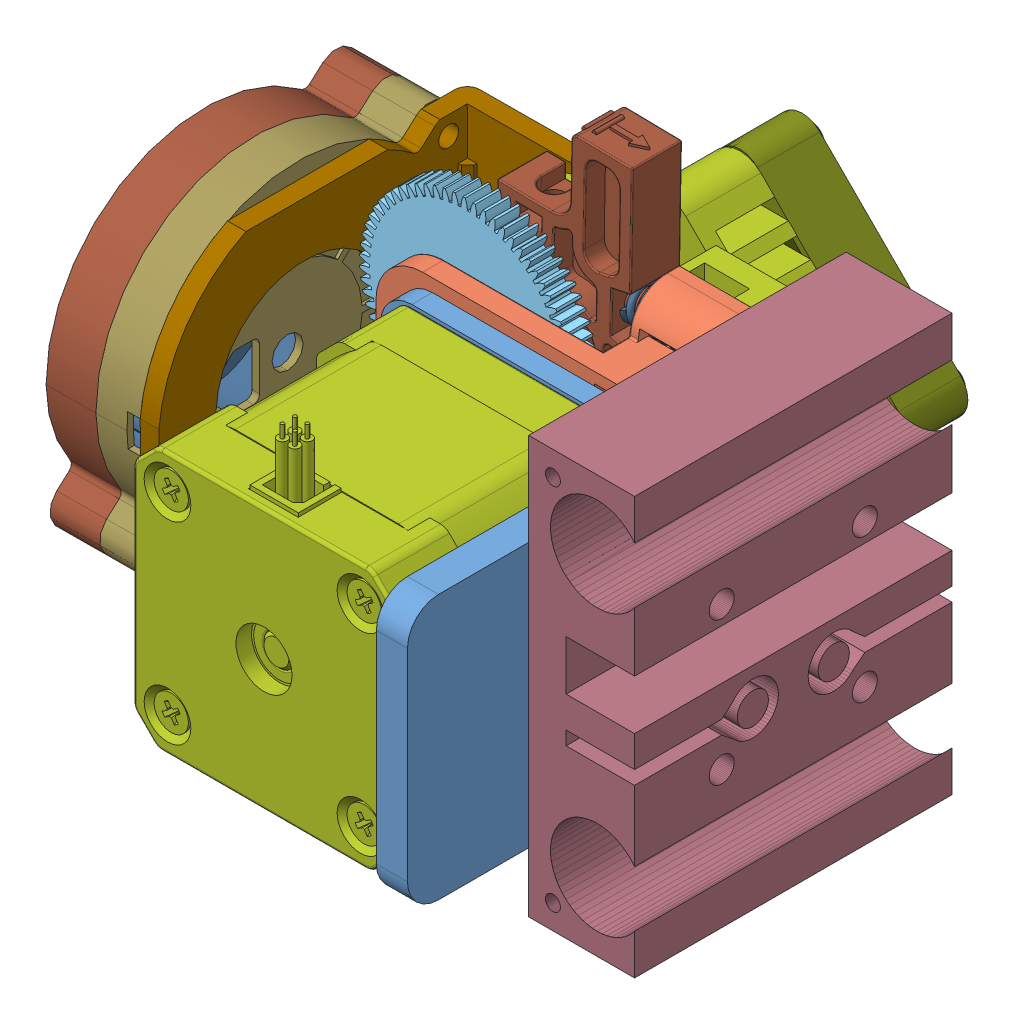
SolidWorks assembly soportetitan, configuration Predeterminado. Lengths in mm.
Overall size (99.83 91.4 93.62).
41 component instances, 31 part files, 14 mates.
Components (placement in the parent):
- soportetitan-1: soportetitan [Predeterminado] at origin size (59.5 44.5 64.5)
- e3d titan areo 1.751-1: e3d titan areo 1.751 [Predeterminado] at (-26.25 -7.1304 -22.9203) x (1 0 0) z (0 1 0) size (64.29 55.52 89.93)
  - Base-1: Base [Predeterminado] at origin size (46 23.41 49.98)
  - 9x5x3mm bearing-1: 9x5x3mm bearing [Predeterminado] at (-15.5 4 15.5) x (1 0 0) z (0 -1 0) size (9 9 3)
  - hobbed wheel-1: hobbed wheel [Predeterminado] at (-15.5 1.6 15.5) x (-0.447437 0 0.894315) z (0 1 0) size (8.6 8.58 20.6)
  - filament gear-1: filament gear [Predeterminado] at (-15.5 8.55 15.5) x (-0.894315 0 -0.447437) z (0 -1 0) size (34 34 4)
  - motor gear-1: motor gear [Predeterminado] at (0 8.5 0) x (-0.681998 0 -0.731354) z (0 -1 0) size (11.99 11.99 9)
  - cover-1: cover [Predeterminado] at (0 24.9 0) x (1 0 0) z (0 0 -1) size (52.63 28.17 55.14)
  - 9x5x3mm bearing-2: 9x5x3mm bearing [Predeterminado] at (-15.5 22.8 15.5) x (1 0 0) z (0 -1 0) size (9 9 3)
  - m3x8-1: m3x8 [Predeterminado] at (20.7 13.6 23.3) x (0 0 1) z (0 1 0) size (5.69 9.65 5.69)
  - M3 nut-1: M3 nut [Predeterminado] at (16.7 13.6 23.3) x (0 1 0) z (0 0 1) size (6.19 2.71 6.57)
  - idler spring-1: idler spring [Predeterminado] at (14.287 13.6 23.3) x (0 0 1) z (-1 0 0) size (6.43 6.45 12.02)
  - tensioner-1: tensioner [Predeterminado] at (0 13.6 0) x (0 -1 0) z (0.017452 0 0.999848) size (8.2 21.54 50.88)
  - idler bearing pin-1: idler bearing pin [Predeterminado] at (-5.2287 9.6 15.5936) x (0.999848 0 -0.017452) z (0 1 0) size (3.04 3.15 9)
  - idler bearing-1: idler bearing [Predeterminado] at (-5.2287 13.6 15.5936) x (0.999848 0 -0.017452) z (0 1 0) size (10 10 4)
  - guide tube-1: guide tube [Predeterminado] at (-10.9 13.6 -7.9) x (-1 0 0) z (0 0 1) size (10.9 16.1 22.25)
  - ISO 7380 - M3 x 28 v1-1: ISO 7380 - M3 x 28 v1 [Predeterminado] at (-15.5 25.94 15.5) x (0 -1 0) z (0 0 1) size (14.65 5.7 5.7)
  - ISO 7380 - M3 x 28 v1-2: ISO 7380 - M3 x 28 v1 [Predeterminado] at (15.5 25.94 15.5) x (0 -1 0) z (0 0 1) size (14.65 5.7 5.7)
  - ISO 7380 - M3 x 28 v1-3: ISO 7380 - M3 x 28 v1 [Predeterminado] at (15.5 25.94 -15.5) x (0 -1 0) z (0 0 1) size (14.65 5.7 5.7)
  - ISO 7380 - M3 x 28 v1-4: ISO 7380 - M3 x 28 v1 [Predeterminado] at (-21.7 25.94 -14.7) x (0 -1 0) z (0 0 -1) size (14.65 5.7 5.7)
  - Fan 40 X 40 X 10 v4-1: Fan 40 X 40 X 10 v4 [Predeterminado] at (-2.3 40.465 3.8274) x (0.707107 0 0.707107) z (-0.707107 0 0.707107) size (40 10.59 40)
  - E3D v6 HotEnd - Heatbreak-1: E3D v6 HotEnd - Heatbreak [Predeterminado] at (-10.9 13.6 -31.7812) x (0 1 0) z (0 0 -1) size (7 7 21.9)
  - E3D v6 HotEnd - Nozzle-1: E3D v6 HotEnd - Nozzle [Predeterminado] at (-10.9 13.6 -42.2812) x (0 1 0) z (0 0 -1) size (8.08 7 12.5)
  - E3D v6 HotEnd - Heat Block-1: E3D v6 HotEnd - Heat Block [Predeterminado] at (-2.9 -1.9 -38.0312) x (0 1 0) z (1 0 0) size (20 11.5 16)
  - Ceramic Cartridge Heater-1: Ceramic Cartridge Heater [Predeterminado] at (-0.9 6.6 -34.0312) x (0 0 1) z (1 0 0) size (6 18 29.25)
  - Thermistor-1: Thermistor [Predeterminado] at (-7 16.1 -36.0312) x (0 -0.5 0.866025) z (-1 0 0) size (1.5 1.5 7.6)
  - HEXAGON SOCKET HEAD CAP SCREWS_SCB3-4-1: HEXAGON SOCKET HEAD CAP SCREWS_SCB3-4 [Predeterminado] at (-2.4 14.6 -33.2312) x (0 1 0) z (1 0 0) size (5.5 5.5 7)
  - HEXAGON SOCKET HEAD CAP SCREWS_SCB3-10-1: HEXAGON SOCKET HEAD CAP SCREWS_SCB3-10 [Predeterminado] at (-10.9 0.6 -38.0312) x (0 1 0) z (0 0 -1) size (5.5 5.5 13)
  - Flat Washers_PWF3-1: Flat Washers_PWF3 [Predeterminado] at (-2.4 14.6 -33.2312) x (0 1 0) z (1 0 0) size (6 6 0.5)
  - ISO 7380 - M3 x 28 v1-5: ISO 7380 - M3 x 28 v1 [Predeterminado] at (-2.3 45.465 26.4548) x (0 -1 0) z (0.707107 0 0.707107) size (14.65 5.7 5.7)
  - ISO 7380 - M3 x 28 v1-6: ISO 7380 - M3 x 28 v1 [Predeterminado] at (-24.9274 45.465 3.8274) x (0 -1 0) z (0.707107 0 0.707107) size (14.65 5.7 5.7)
  - ISO 7380 - M3 x 28 v1-7: ISO 7380 - M3 x 28 v1 [Predeterminado] at (-2.3 45.465 -18.8) x (0 -1 0) z (0.707107 0 0.707107) size (14.65 5.7 5.7)
  - ISO 7380 - M3 x 28 v1-8: ISO 7380 - M3 x 28 v1 [Predeterminado] at (20.3274 45.465 3.8274) x (0 -1 0) z (0.707107 0 0.707107) size (14.65 5.7 5.7)
- 17HM15-0904S-1: 17HM15-0904S [По умолчанию] at (-26.25 -7.1304 20.3797) x (1 0 0) z (0 1 0) size (42.3 62 51.35)
- BLTouch-1: BLTouch [Predeterminado] at (-53.5 -10.3804 -9.9203) x (0 0 -1) z (1 0 0) size (26 42.5 11.53)
- tobera5015s-1: tobera5015s [Predeterminado] at (-84.0045 -15.0003 -51.8603) x (0.999981 0.006108 0) z (0 0 1) size (44.33 68.4 52.67)
- Radial-Cooling-Fan-5015-DC12V-1: Radial-Cooling-Fan-5015-DC12V [По умолчанию] at (-65.6943 -5.7769 -22.8603) x (0 0 1) z (0.006108 -0.999981 0) size (51.3 15 51.07)
  - turbine-1: turbine [По умолчанию] at (0 3.2 0) x (0.990476 0 -0.137682) z (0.137682 0 0.990476) size (38.96 10.5 38.91)
  - top-3: top [По умолчанию] at (0 15 0) size (51.3 8 51.07)
  - bottom-1: bottom [По умолчанию] at origin size (51.3 8.5 51.07)
- xcarriage-1: xcarriage [Predeterminado] at (0 29.0054 5.093) x (0 0 -1) z (1 0 0) size (51 67 17)
Mates (geometry in assembly coordinates):
- Concéntrica5: concentric anti-aligned: circle of soportetitan-1; circle of e3d titan areo 1.751-1/Base-1
- Concéntrica6: concentric anti-aligned: circle of soportetitan-1; circle of e3d titan areo 1.751-1/Base-1
- Coincidente16: coincident anti-aligned: plane of soportetitan-1 through (0 0 -22.9203) normal (0 0 -1); plane of e3d titan areo 1.751-1/Base-1 through (-28.55 -5.8304 -22.9203) normal (0 0 1)
- Coincidente17: coincident anti-aligned: plane of e3d titan areo 1.751-1/cover-1 through (-28.55 -5.8304 -48.8603) normal (0 0 -1); plane of tobera5015s-1 through (-46.4608 11.7612 -48.8603) normal (0 0 1)
- Concéntrica7: concentric aligned: circle of e3d titan areo 1.751-1/ISO 7380 - M3 x 28 v1-1; circle of tobera5015s-1
- Coincidente18: coincident anti-aligned: plane of tobera5015s-1 through (-65.6387 -14.8881 -51.8603) normal (-0.999981 -0.006108 0); plane of Radial-Cooling-Fan-5015-DC12V-1/bottom-1 through (-65.8165 14.2228 -45.8603) normal (0.999981 0.006108 0)
- Concéntrica14: concentric aligned: circle of tobera5015s-1; circle of Radial-Cooling-Fan-5015-DC12V-1/bottom-1
- Concéntrica15: concentric aligned: circle of tobera5015s-1; circle of Radial-Cooling-Fan-5015-DC12V-1/bottom-1
- Concéntrica16: concentric anti-aligned: circle of soportetitan-1; circle of 17HM15-0904S-1
- Concéntrica17: concentric anti-aligned: circle of soportetitan-1; circle of 17HM15-0904S-1
- Coincidente19: coincident anti-aligned: plane of soportetitan-1 through (-42.5 -23.3804 -19.6203) normal (0 0 1); plane of 17HM15-0904S-1 through (-26.25 -7.1304 -19.6203) normal (0 0 -1)
- Coincidente20: coincident anti-aligned: plane of soportetitan-1 through (0 0 0) normal (1 0 0); plane of xcarriage-1 through (0 29.0054 5.093) normal (-1 0 0)
- Coincidente21: coincident: plane of soportetitan-1 through (-55.5 -10.3804 -0.9203) normal (0 -1 0); plane of BLTouch-1 through (-53.5 -10.3804 -18.9203) normal (0 1 0)
- Coincidente22: coincident aligned: circle of soportetitan-1; circle of BLTouch-1
